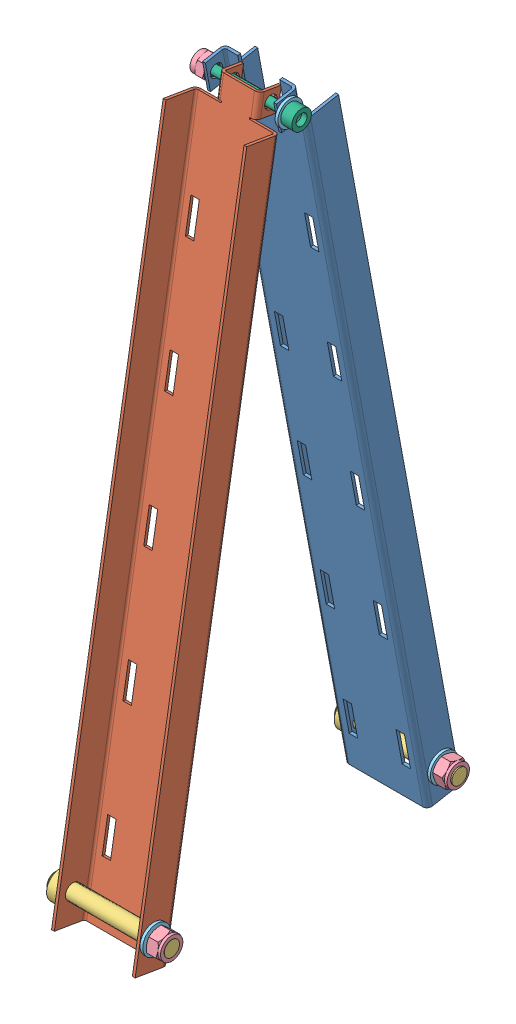
SolidWorks assembly BRAÇO ARTICULADO, configuration Valor predeterminado. Lengths in mm.
Overall size (41.8 250.93 116.88).
13 component instances, 7 part files, 23 mates.
Components (placement in the parent):
- 500220100-1: 500220100 [Valor predeterminado] at (-0.0208 244.8012 -230.8861) x (1 0 0) z (0 0.9832 0.18253) size (30 19 250)
- 500210100-1: 500210100 [Valor predeterminado] at (29.9792 243.7483 -222.8744) x (-1 0 0) z (0 0.986165 -0.165766) size (30 19 250)
- 500240100-1: 500240100 [Valor predeterminado] at (-3.5208 8.0414 -177.3034) x (0 0.979496 0.201464) z (1 0 0) size (10 10 39.95)
- 500240100-2: 500240100 [Valor predeterminado] at (-3.5208 9.9043 -280.4632) x (0 -0.998505 -0.054657) z (1 0 0) size (10 10 39.95)
- PORCA AUTO TRAVANTE DIN 982-1: PORCA AUTO TRAVANTE DIN 982 [M05 DIN 982] at (31.3572 8.0414 -177.3034) x (0 0.983023 -0.183483) z (1 0 0) size (9.24 8 5)
- ARRUELA LISA DIN 125-1: ARRUELA LISA DIN 125 [DIN 125 - A5,3] at (30.4792 8.0414 -177.3034) x (0 0.50991 -0.860228) z (-1 0 0) size (10 10 1)
- ARRUELA LISA DIN 125-2: ARRUELA LISA DIN 125 [DIN 125 - A5,3] at (30.4792 9.9043 -280.4632) x (0 -0.460473 0.887674) z (1 0 0) size (10 10 1)
- PORCA AUTO TRAVANTE DIN 982-2: PORCA AUTO TRAVANTE DIN 982 [M05 DIN 982] at (30.9792 9.9043 -280.4632) x (0 0.202528 0.979277) z (1 0 0) size (9.24 8 5)
- PORCA AUTO TRAVANTE DIN 982-3: PORCA AUTO TRAVANTE DIN 982 [M04 DIN 982] at (1.7158 238.9966 -227.0123) x (0 -0.973177 0.23006) z (-1 0 0) size (8.08 7 5)
- PARAFUSO ALLEN CILÍNDRICO DIN 912-1: PARAFUSO ALLEN CILÍNDRICO DIN 912 [M4x30] at (33.2426 238.9966 -227.0123) x (0 -0.831156 0.55604) z (-1 0 0) size (7 7 34)
- ARRUELA LISA DIN 125-3: ARRUELA LISA DIN 125 [DIN 125 - A4,3] at (28.7426 238.9966 -227.0123) x (0 0.632288 -0.774733) z (-1 0 0) size (9 9 1)
- PARAFUSO ALLEN CÔNICO DIN 7991-1: PARAFUSO ALLEN CÔNICO DIN 7991 [M3x10] at (4.6292 9.9043 -280.4632) x (-1 0 0) z (0 -0.965547 -0.260228) size (10 6 6)
- PARAFUSO ALLEN CÔNICO DIN 7991-2: PARAFUSO ALLEN CÔNICO DIN 7991 [M3x10] at (4.6292 8.0414 -177.3034) x (-1 0 0) z (0 -0.899636 -0.436641) size (10 6 6)
Mates (geometry in assembly coordinates):
- Concêntrico421: concentric anti-aligned: cylinder of 500220100-1 through (1.7158 65.2514 -51.8216) axis (-1 0 0) radius 2.25; cylinder of 500210100-1 through (22.2426 65.2514 -51.8216) axis (1 0 0) radius 2.25
- Largura111: width aligned: plane of 500210100-1 through (22.2426 69.6094 -47.271) normal (1 0 0); plane of 500210100-1 through (7.7158 69.6094 -47.271) normal (-1 0 0); plane of 500220100-1 through (2.7158 71.3227 -48.3808) normal (1 0 0); plane of 500220100-1 through (27.2426 71.3227 -48.3808) normal (-1 0 0)
- Concêntrico483: concentric anti-aligned: cylinder of 500220100-1 through (29.9792 9.9043 -280.4632) axis (1 0 0) radius 2.75; cylinder of 500240100-2 through (36.4292 9.9043 -280.4632) axis (-1 0 0) radius 2.75
- Coincidente1045: coincident anti-aligned: plane of 500220100-1 through (29.9792 71.3227 -48.3808) normal (1 0 0); plane of ARRUELA LISA DIN 125-2 through (29.9792 9.9043 -280.4632) normal (-1 0 0)
- Concêntrico493: concentric anti-aligned: cylinder of 500220100-1 through (1.7158 65.2514 -51.8216) axis (-1 0 0) radius 2.25; cylinder of ARRUELA LISA DIN 125-3 through (28.2426 65.2514 -51.8216) axis (1 0 0) radius 2.15
- Coincidente1050: coincident anti-aligned: plane of 500220100-1 through (28.2426 71.3227 -48.3808) normal (1 0 0); plane of ARRUELA LISA DIN 125-3 through (28.2426 65.2514 -51.8216) normal (-1 0 0)
- Concêntrico495: concentric anti-aligned: cylinder of 500220100-1 through (1.7158 65.2514 -51.8216) axis (-1 0 0) radius 2.25; cylinder of PORCA AUTO TRAVANTE DIN 982-3 through (-1.4842 65.2514 -51.8216) axis (1 0 0) radius 2
- Coincidente1084: coincident anti-aligned: plane of 500220100-1 through (1.7158 71.3227 -48.3808) normal (-1 0 0); plane of PORCA AUTO TRAVANTE DIN 982-3 through (1.7158 61.3183 -50.8918) normal (1 0 0)
- Concêntrico482: concentric aligned: cylinder of 500210100-1 through (-0.0208 -169.2526 -23.2004) axis (-1 0 0) radius 2.75; cylinder of 500240100-1 through (36.4292 -169.2526 -23.2004) axis (-1 0 0) radius 2.75
- Coincidente1044: coincident anti-aligned: plane of 500210100-1 through (29.9792 69.6094 -47.271) normal (1 0 0); plane of ARRUELA LISA DIN 125-1 through (29.9792 -169.2526 -23.2004) normal (-1 0 0)
- Concêntrico492: concentric aligned: cylinder of 500210100-1 through (22.2426 65.2514 -51.8216) axis (1 0 0) radius 2.25; cylinder of PARAFUSO ALLEN CILÍNDRICO DIN 912-1 through (-0.7574 65.2514 -51.8216) axis (1 0 0) radius 1.6
- Concêntrico484: concentric aligned: cylinder of 500240100-1 through (36.4292 -169.2526 -23.2004) axis (-1 0 0) radius 2.75; cylinder of PORCA AUTO TRAVANTE DIN 982-1 through (35.3572 -169.2526 -23.2004) axis (-1 0 0) radius 2.5
- Concêntrico485: concentric anti-aligned: cylinder of 500240100-1 through (36.4292 -169.2526 -23.2004) axis (-1 0 0) radius 2.75; cylinder of ARRUELA LISA DIN 125-1 through (29.9792 -169.2526 -23.2004) axis (1 0 0) radius 2.65
- Concêntrico497: concentric: cylinder of 500240100-1 through (-3.5208 8.0414 -177.3034) axis (-1 0 0) radius 1.25; cylinder of PARAFUSO ALLEN CÔNICO DIN 7991-2 through (8.8461 8.0414 -177.3034) axis (1 0 0) radius 1.25
- Concêntrico486: concentric aligned: cylinder of 500240100-2 through (36.4292 9.9043 -280.4632) axis (-1 0 0) radius 2.75; cylinder of ARRUELA LISA DIN 125-2 through (30.9792 9.9043 -280.4632) axis (-1 0 0) radius 2.65
- Concêntrico487: concentric aligned: cylinder of 500240100-2 through (36.4292 9.9043 -280.4632) axis (-1 0 0) radius 2.75; cylinder of PORCA AUTO TRAVANTE DIN 982-2 through (34.9792 9.9043 -280.4632) axis (-1 0 0) radius 2.5
- Concêntrico496: concentric: cylinder of 500240100-2 through (-3.5208 9.9043 -280.4632) axis (-1 0 0) radius 1.25; cylinder of PARAFUSO ALLEN CÔNICO DIN 7991-1 through (7.615 9.9043 -280.4632) axis (1 0 0) radius 1.25
- Coincidente1046: coincident anti-aligned: plane of ARRUELA LISA DIN 125-2 through (30.9792 9.9043 -280.4632) normal (1 0 0); plane of PORCA AUTO TRAVANTE DIN 982-2 through (30.9792 10.8397 -275.9401) normal (-1 0 0)
- Coincidente1051: coincident anti-aligned: plane of PARAFUSO ALLEN CILÍNDRICO DIN 912-1 through (29.2426 65.2514 -51.8216) normal (-1 0 0); plane of ARRUELA LISA DIN 125-3 through (29.2426 65.2514 -51.8216) normal (1 0 0)
- Deckungsgleich1: coincident anti-aligned: plane of 500220100-1 through (-0.0208 71.3227 -48.3808) normal (-1 0 0); plane of 500240100-2 through (-0.0208 9.9043 -280.4632) normal (1 0 0)
- Deckungsgleich2: coincident anti-aligned: plane of 500210100-1 through (-0.0208 69.6094 -47.271) normal (-1 0 0); plane of 500240100-1 through (-0.0208 -169.2526 -23.2004) normal (1 0 0)
- Deckungsgleich3: coincident anti-aligned: plane of 500240100-2 through (-3.5208 9.9043 -280.4632) normal (-1 0 0); circle of PARAFUSO ALLEN CÔNICO DIN 7991-1
- Deckungsgleich4: coincident anti-aligned: plane of 500240100-1 through (-3.5208 8.0414 -177.3034) normal (-1 0 0); circle of PARAFUSO ALLEN CÔNICO DIN 7991-2
